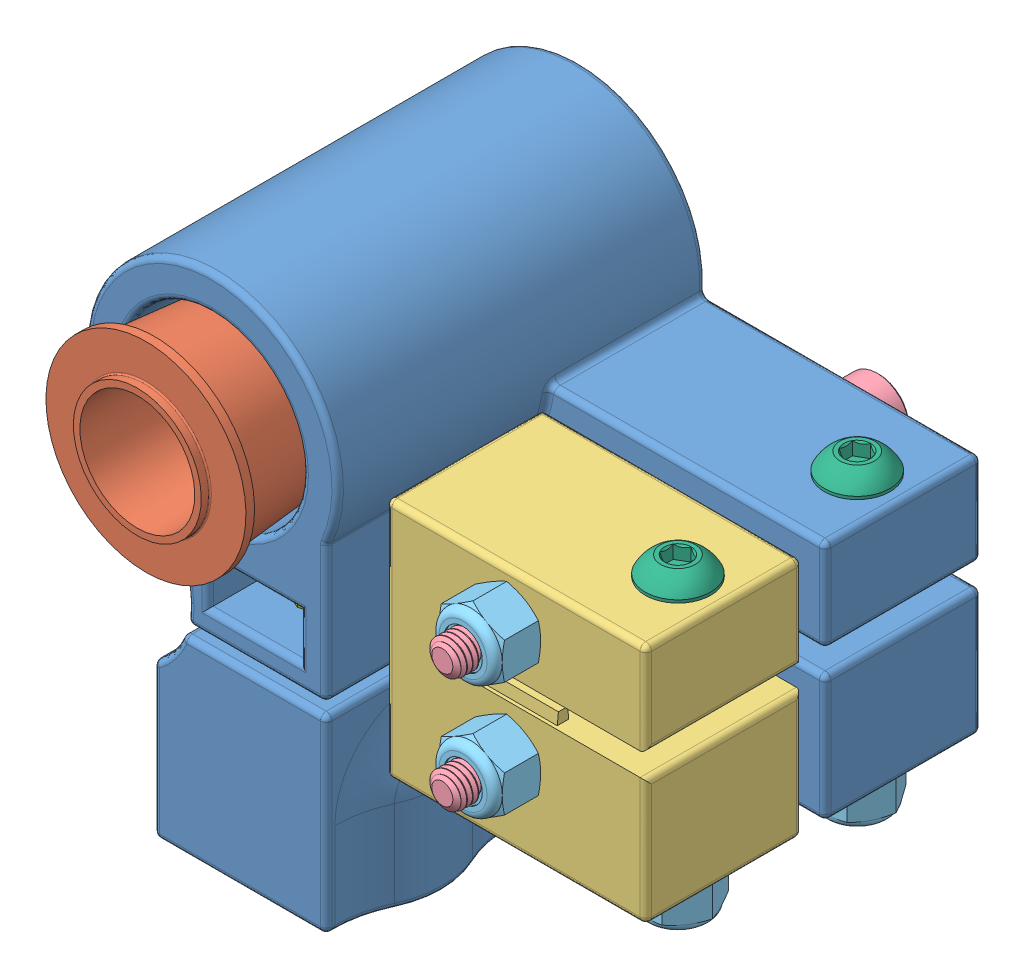
SolidWorks assembly XY_Axis_Belt_Tensioner_B, configuration Default. Lengths in mm.
Overall size (46.04 45 41.58).
14 component instances, 8 part files, 28 mates.
Components (placement in the parent):
- XY Axis Belt Tensioner B-1: XY Axis Belt Tensioner B [Default] at origin size (46 45 32.06)
- a_7z41mpsb10m-1: a_7z41mpsb10m [Default] at (5 34 53.6866) x (1 0 0) z (0 1 0) size (17.4 11.55 17.4)
- a_7z41mpsb10m-2: a_7z41mpsb10m [Default] at (5 34 15.25) x (1 0 0) z (0 -1 0) size (17.4 11.55 17.4)
- XY Axis Belt Tensioner End-1: XY Axis Belt Tensioner End [Default] at (0 0 29.2) size (22.6 21 13.6)
- 3mmX35mm_Sockethead(McMaster_91290A135)-1: 3mmX35mm_Sockethead(McMaster_91290A135) [91290A135] at (28.1 28.85 51) size (5.5 5.5 38.26)
- 3mmX35mm_Sockethead(McMaster_91290A135)-2: 3mmX35mm_Sockethead(McMaster_91290A135) [91290A135] at (28.1 18.85 51) size (5.5 5.5 38.26)
- 3mm_Hex_Nylock_Nut(McMaster_90576A102)-1: 3mm_Hex_Nylock_Nut(McMaster_90576A102) [90576A102] at (28.1 28.85 45.2) x (1 0 0) z (0 -1 0) size (5.5 4.1 6.35)
- 3mm_Hex_Nylock_Nut(McMaster_90576A102)-2: 3mm_Hex_Nylock_Nut(McMaster_90576A102) [90576A102] at (28.1 18.85 45.2) x (1 0 0) z (0 -1 0) size (5.5 4.1 6.35)
- 3mmX25mm_Buttonhead(McMaster_91239A126)-1: 3mmX25mm_Buttonhead(McMaster_91239A126) [91239A126] at (36 34.5 38.4) x (1 0 0) z (0 1 0) size (5.7 5.7 27.01)
- 3mmX25mm_Buttonhead(McMaster_91239A126)-2: 3mmX25mm_Buttonhead(McMaster_91239A126) [91239A126] at (36 34.5 22.8) x (1 0 0) z (0 1 0) size (5.7 5.7 27.01)
- 3mm_Hex_Nylock_Nut(McMaster_90576A102)-3: 3mm_Hex_Nylock_Nut(McMaster_90576A102) [90576A102] at (36 11.85 22.8) x (-0.89673 0 -0.442578) z (-0.442578 0 0.89673) size (5.5 4.1 6.35)
- 3mm_Hex_Nylock_Nut(McMaster_90576A102)-4: 3mm_Hex_Nylock_Nut(McMaster_90576A102) [90576A102] at (36 11.85 38.4) x (-0.836969 0 -0.54725) z (-0.54725 0 0.836969) size (5.5 4.1 6.35)
- 5mm_Hex_Nut(McMaster_90591A146)-1: 5mm_Hex_Nut(McMaster_90591A146) [90591A146] at (8.7 21.5 39.6) size (8 4.31 9.24)
- 5mmX16mm_Buttonhead(McMaster_91239A232)-1: 5mmX16mm_Buttonhead(McMaster_91239A232) [91239A232] at (8.7 3.25 39.6) x (-0.995484 0 0.094925) z (0 -1 0) size (9.5 9.5 19.24)
Mates (geometry in assembly coordinates):
- Concentric3: concentric aligned: circle of a_7z41mpsb10m-1; cylinder of XY Axis Belt Tensioner B-1 through (5 34 37) axis (0 0 1) radius 7.95
- Coincident3: coincident anti-aligned: plane of XY Axis Belt Tensioner B-1 through (-4 19 48) normal (0 0 1); plane of a_7z41mpsb10m-1 through (5 34 48) normal (0 0 -1)
- Concentric4: concentric aligned: cylinder of XY Axis Belt Tensioner B-1 through (5 34 27) axis (0 0 -1) radius 7.95; circle of a_7z41mpsb10m-2
- Coincident4: coincident anti-aligned: plane of XY Axis Belt Tensioner B-1 through (-4 19 16) normal (0 0 -1); plane of a_7z41mpsb10m-2 through (5 34 16) normal (0 0 1)
- Concentric262: concentric anti-aligned: cylinder of XY Axis Belt Tensioner B-1 through (28.1 28.85 16) axis (0 0 1) radius 1.6; cylinder of XY Axis Belt Tensioner End-1 through (28.1 28.85 45.2) axis (0 0 -1) radius 1.6
- Concentric263: concentric anti-aligned: cylinder of XY Axis Belt Tensioner B-1 through (28.1 18.85 16) axis (0 0 1) radius 1.6; cylinder of XY Axis Belt Tensioner End-1 through (28.1 18.85 45.2) axis (0 0 -1) radius 1.6
- Distance1: distance = 2 mm anti-aligned: plane of XY Axis Belt Tensioner End-1 through (0 0 31.6) normal (0 0 -1); plane of XY Axis Belt Tensioner B-1 through (0 0 29.6) normal (0 0 1)
- Concentric264: concentric aligned: cylinder of XY Axis Belt Tensioner B-1 through (28.1 28.85 16) axis (0 0 1) radius 1.6; cylinder of 3mmX35mm_Sockethead(McMaster_91290A135)-1 through (28.1 28.85 16) axis (0 0 1) radius 1.5
- Concentric265: concentric aligned: cylinder of XY Axis Belt Tensioner B-1 through (28.1 18.85 16) axis (0 0 1) radius 1.6; cylinder of 3mmX35mm_Sockethead(McMaster_91290A135)-2 through (28.1 18.85 16) axis (0 0 1) radius 1.5
- Coincident273: coincident anti-aligned: plane of XY Axis Belt Tensioner B-1 through (-4 19 16) normal (0 0 -1); plane of 3mmX35mm_Sockethead(McMaster_91290A135)-2 through (28.1 18.85 16) normal (0 0 1)
- Coincident274: coincident anti-aligned: plane of XY Axis Belt Tensioner B-1 through (-4 19 16) normal (0 0 -1); plane of 3mmX35mm_Sockethead(McMaster_91290A135)-1 through (28.1 28.85 16) normal (0 0 1)
- Concentric266: concentric anti-aligned: cylinder of XY Axis Belt Tensioner End-1 through (36 7.3245 38.4) axis (0 1 0) radius 1.6; cylinder of 3mmX25mm_Buttonhead(McMaster_91239A126)-1 through (36 7.85 38.4) axis (0 -1 0) radius 1.5
- Coincident275: coincident anti-aligned: plane of XY Axis Belt Tensioner End-1 through (40 32.85 45.2) normal (0 1 0); plane of 3mmX25mm_Buttonhead(McMaster_91239A126)-1 through (36 32.85 41.25) normal (0 -1 0)
- Concentric267: concentric anti-aligned: cylinder of XY Axis Belt Tensioner B-1 through (36 7.3245 22.8) axis (0 1 0) radius 1.6; cylinder of 3mmX25mm_Buttonhead(McMaster_91239A126)-2 through (36 7.85 22.8) axis (0 -1 0) radius 1.5
- Coincident276: coincident anti-aligned: plane of XY Axis Belt Tensioner B-1 through (40 32.85 16) normal (0 1 0); plane of 3mmX25mm_Buttonhead(McMaster_91239A126)-2 through (36 32.85 25.65) normal (0 -1 0)
- Concentric268: concentric aligned: cylinder of XY Axis Belt Tensioner End-1 through (28.1 28.85 45.2) axis (0 0 -1) radius 1.6; circle of 3mm_Hex_Nylock_Nut(McMaster_90576A102)-1
- Coincident277: coincident anti-aligned: plane of XY Axis Belt Tensioner End-1 through (-4 19 45.2) normal (0 0 1); plane of 3mm_Hex_Nylock_Nut(McMaster_90576A102)-1 through (28.1 32.0254 45.2) normal (0 0 -1)
- Concentric269: concentric aligned: cylinder of XY Axis Belt Tensioner End-1 through (28.1 18.85 45.2) axis (0 0 -1) radius 1.6; circle of 3mm_Hex_Nylock_Nut(McMaster_90576A102)-2
- Coincident278: coincident anti-aligned: plane of XY Axis Belt Tensioner End-1 through (-4 19 45.2) normal (0 0 1); plane of 3mm_Hex_Nylock_Nut(McMaster_90576A102)-2 through (28.1 22.0254 45.2) normal (0 0 -1)
- Concentric270: concentric aligned: cylinder of XY Axis Belt Tensioner End-1 through (36 7.3245 38.4) axis (0 1 0) radius 1.6; cylinder of 3mm_Hex_Nylock_Nut(McMaster_90576A102)-4 through (36 8.4405 38.4) axis (0 1 0) radius 1.269
- Coincident279: coincident anti-aligned: plane of XY Axis Belt Tensioner End-1 through (23 11.85 45.2) normal (0 -1 0); plane of 3mm_Hex_Nylock_Nut(McMaster_90576A102)-4 through (37.7378 11.85 35.7423) normal (0 1 0)
- Concentric271: concentric aligned: cylinder of XY Axis Belt Tensioner B-1 through (36 7.3245 22.8) axis (0 1 0) radius 1.6; cylinder of 3mm_Hex_Nylock_Nut(McMaster_90576A102)-3 through (36 8.4405 22.8) axis (0 1 0) radius 1.269
- Coincident280: coincident anti-aligned: plane of XY Axis Belt Tensioner B-1 through (23 11.85 16) normal (0 -1 0); plane of 3mm_Hex_Nylock_Nut(McMaster_90576A102)-3 through (37.4054 11.85 19.9525) normal (0 1 0)
- Concentric272: concentric aligned: cylinder of XY Axis Belt Tensioner B-1 through (8.7 25 39.6) axis (0 -1 0) radius 2.6; cylinder of 5mmX16mm_Buttonhead(McMaster_91239A232)-1 through (8.7 3.25 39.6) axis (0 -1 0) radius 4.75
- Concentric273: concentric aligned: cylinder of XY Axis Belt Tensioner B-1 through (8.7 25 39.6) axis (0 -1 0) radius 2.6; circle of 5mm_Hex_Nut(McMaster_90591A146)-1
- Coincident281: coincident anti-aligned: plane of XY Axis Belt Tensioner B-1 through (12.725 19.5 33.1) normal (0 1 0); plane of 5mm_Hex_Nut(McMaster_90591A146)-1 through (4.7 19.5 32.6718) normal (0 -1 0)
- Parallel1: parallel anti-aligned: plane of XY Axis Belt Tensioner B-1 through (4.675 23.5 33.1) normal (1 0 0); plane of 5mm_Hex_Nut(McMaster_90591A146)-1 through (4.7 23.5 37.2906) normal (-1 0 0)
- Coincident283: coincident anti-aligned: plane of XY Axis Belt Tensioner B-1 through (8.7 6 39.6) normal (0 -1 0); plane of 5mmX16mm_Buttonhead(McMaster_91239A232)-1 through (9.1509 6 44.3286) normal (0 1 0)
